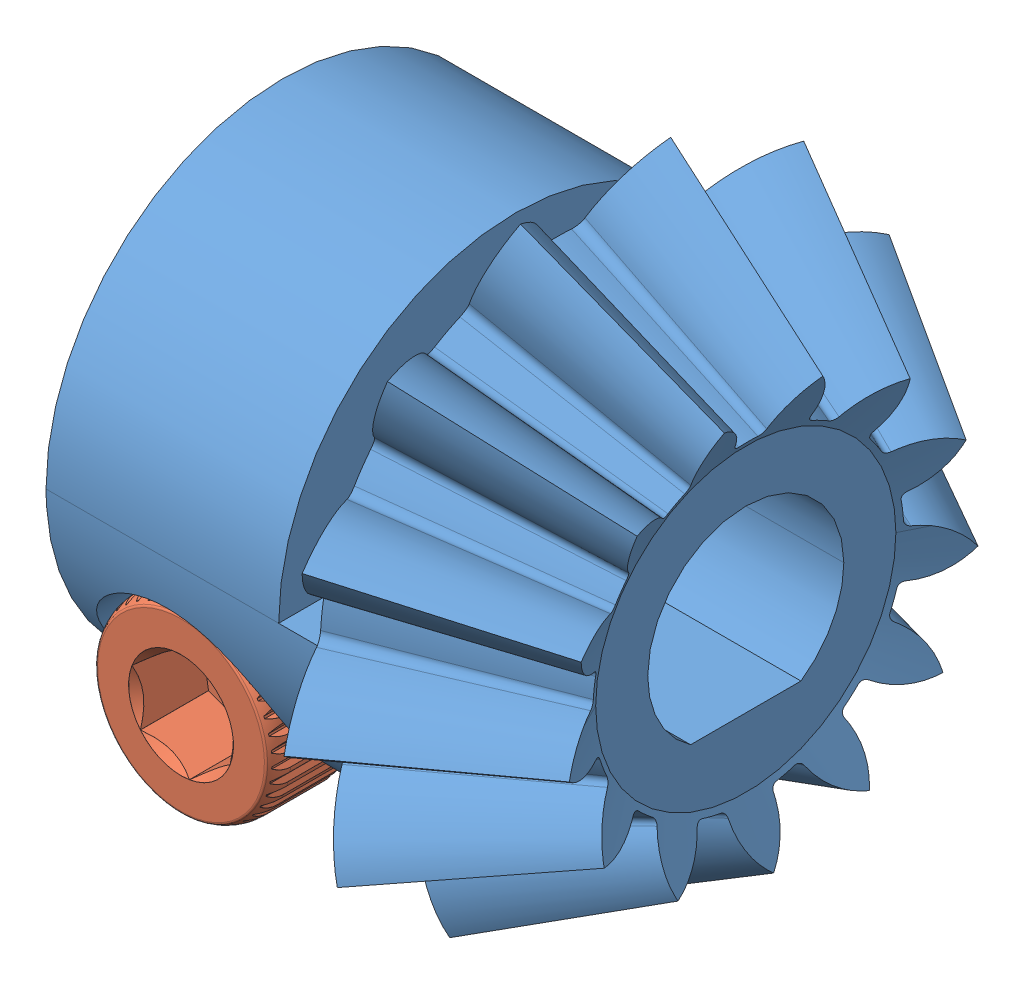
SolidWorks assembly 615458 assembly, configuration Default. Lengths in mm.
Overall size (15.16 19.24 19.22).
2 component instances, 2 part files, 0 mates.
Components (placement in the parent):
- 615458.STEP-1: 615458.STEP [Default] at (-61.4441 5.8673 28.8984) size (15.1 19.24 19.22)
- 632110_90128A121.STEP-1: 632110_90128A121.STEP [Default] at (-66.148 1.368 -6.0266) x (-0.354662 -0.934995 0) z (0 0 -1) size (5.61 5.61 13.03)
